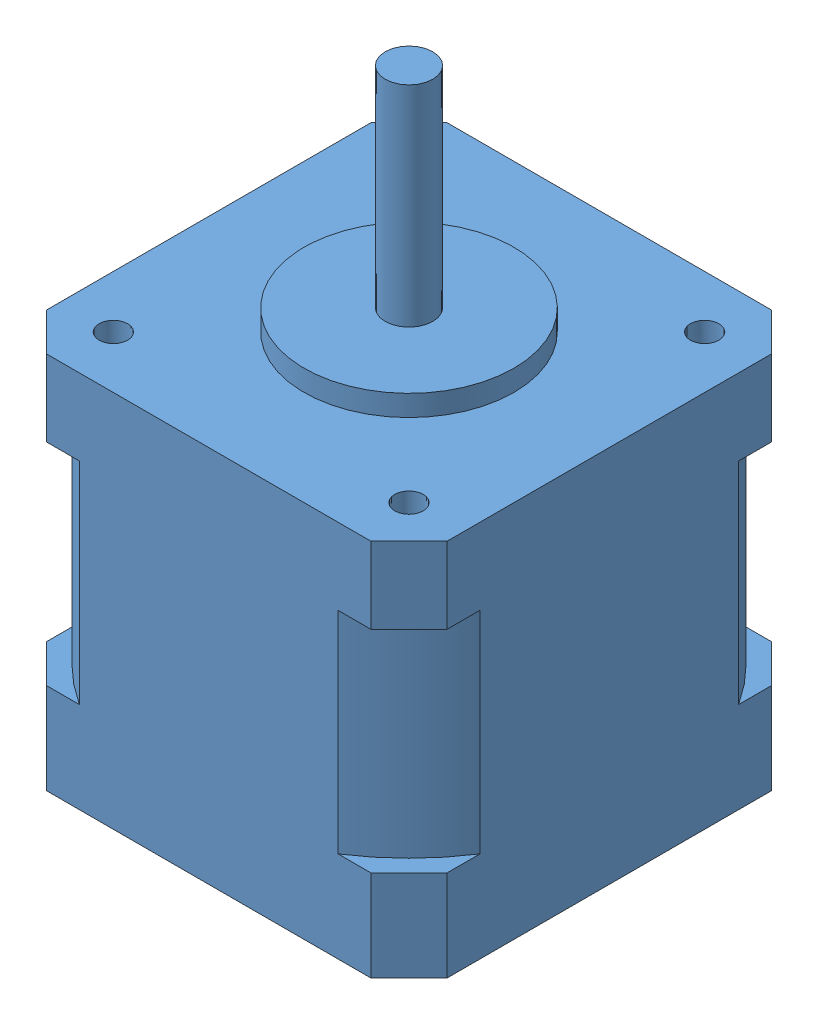
SolidWorks assembly NEMA17, configuration Default. Lengths in mm.
Overall size (42 63.87 42).
3 component instances, 3 part files, 8 mates.
Components (placement in the parent):
- BASE_AS5600-1: BASE_AS5600 [Default] at (-11.1333 23.0507 53.6357) x (1 0 0) z (0 -1 0) size (42 42 9.55) (hidden)
- NEMA17-1: NEMA17 [Default] at (-11.1333 23.0507 53.6357) x (-1 0 0) z (0 1 0) size (42 42 54.32) (hidden)
- NEMA17-SOLID-1: NEMA17-SOLID [Default] at (-11.1333 53.1707 53.6357) x (-1 0 0) z (0 1 0) size (42 42 63.87)
Mates (geometry in assembly coordinates):
- InPlace1: in place: plane of BASE_AS5600-1 through (-11.1333 23.0507 53.6357) normal (0 1 0); plane of ? through (0 23.0507 0) normal (0 1 0); moOrthogonalPlaneRef_w of BASE_AS5600-1 through (-11.1333 23.0507 53.6357) normal (0 1 0); plane of ? through (0 23.0507 0) normal (0 0 -1); plane of BASE_AS5600-1 through (-11.1333 23.0507 53.6357) normal (0 1 0); plane of ? through (0 23.0507 0) normal (1 0 0); plane of BASE_AS5600-1 through (-11.1333 23.0507 53.6357) normal (0 1 0); unknown of NEMA17-1
- Coincident1: coincident aligned: plane of ?; plane of ?
- Coincident2: coincident aligned: moOrthogonalPlaneRef_w of BASE_AS5600-1 through (-11.1333 23.0507 53.6357) normal (0 0 1); plane of Part1^Assem1-1 through (-11.1333 23.0507 53.6357) normal (0 0 1)
- Coincident3: coincident anti-aligned: moOrthogonalPlaneRef_w of BASE_AS5600-1 through (-11.1333 23.0507 53.6357) normal (1 0 0); plane of Part1^Assem1-1 through (-11.1333 23.0507 53.6357) normal (-1 0 0)
- InPlace2: in place: plane of NEMA17-1 through (-11.1333 53.1707 53.6357) normal (0 1 0); plane of ? through (0 53.1707 0) normal (0 1 0); plane of NEMA17-1 through (-11.1333 53.1707 53.6357) normal (0 1 0); plane of ? through (0 53.1707 0) normal (0 0 -1); plane of NEMA17-1 through (-11.1333 53.1707 53.6357) normal (0 1 0); plane of ? through (0 53.1707 0) normal (1 0 0); plane of NEMA17-1 through (-11.1333 53.1707 53.6357) normal (0 1 0); unknown of NEMA17-SOLID-1
- Coincident1: coincident aligned: plane of ?; plane of ?
- Coincident2: coincident aligned: moOrthogonalPlaneRef_w of NEMA17-1 through (-11.1333 53.1707 53.6357) normal (0 0 1); plane of Part4^NEMA17-1 through (-11.1333 53.1707 53.6357) normal (0 0 1)
- Coincident3: coincident anti-aligned: moOrthogonalPlaneRef_w of NEMA17-1 through (-11.1333 53.1707 53.6357) normal (1 0 0); plane of Part4^NEMA17-1 through (-11.1333 53.1707 53.6357) normal (-1 0 0)
